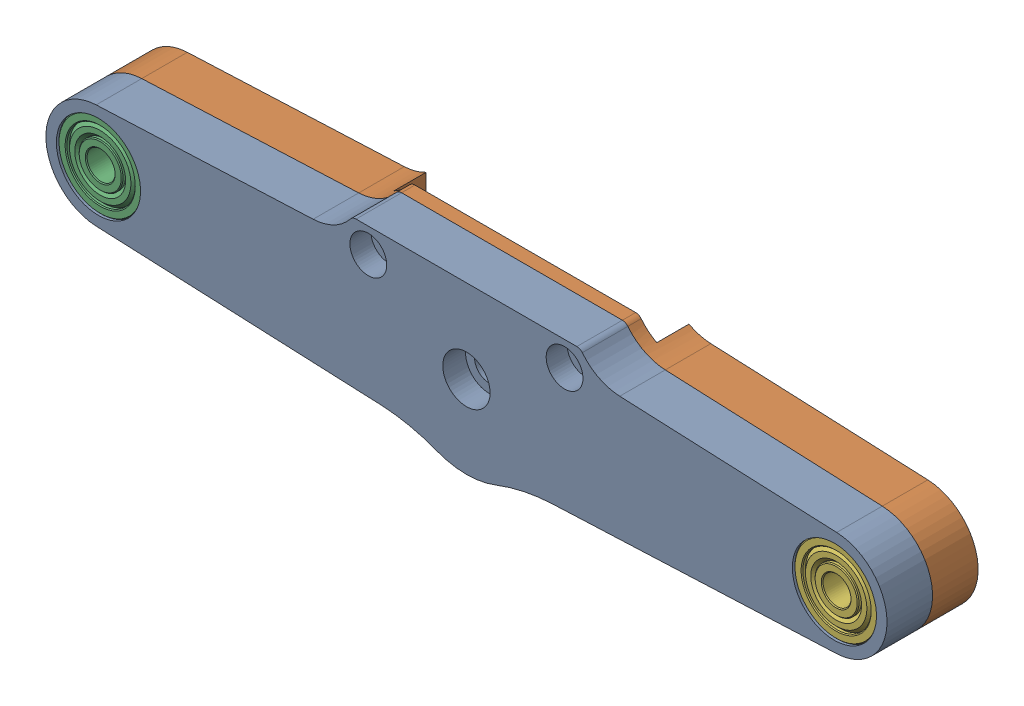
SolidWorks assembly MFG CW Fwd Linkage Asmbly, configuration Default. Lengths in mm.
Overall size (240 47.35 26).
6 component instances, 3 part files, 0 mates.
Components (placement in the parent):
- MFG CW Fwd Linkage Upper-1: MFG CW Fwd Linkage Upper [Default] at origin size (240 47.35 13)
- MFG CW Fwd Linkage Lower-1: MFG CW Fwd Linkage Lower [Default] at origin size (240 47.35 13)
- 628Z 8x24x8mm Ball Bearing-1: 628Z 8x24x8mm Ball Bearing [Default] at (-105 189 74) size (24 24 8)
- 628Z 8x24x8mm Ball Bearing-2: 628Z 8x24x8mm Ball Bearing [Default] at (-105 189 58.5) size (24 24 8)
- 628Z 8x24x8mm Ball Bearing-3: 628Z 8x24x8mm Ball Bearing [Default] at (105 189 58.5) size (24 24 8)
- 628Z 8x24x8mm Ball Bearing-4: 628Z 8x24x8mm Ball Bearing [Default] at (105 189 74) size (24 24 8)
